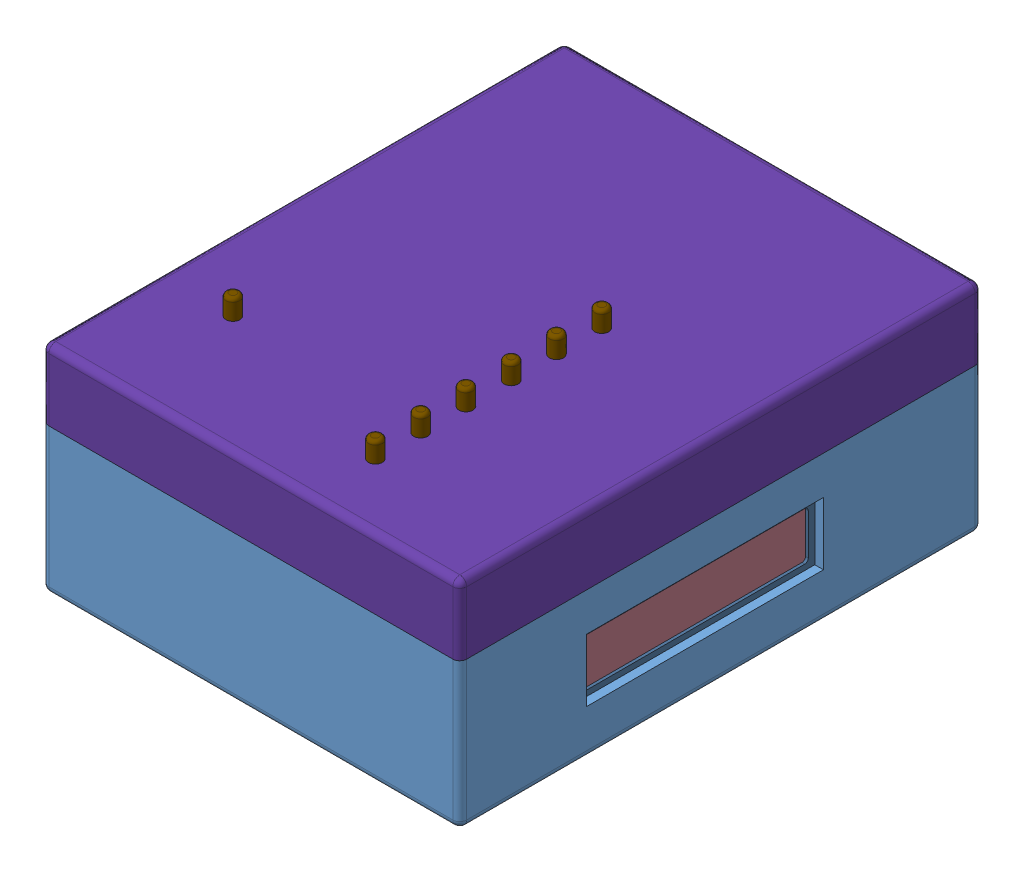
SolidWorks assembly final_enclosure, configuration Default. Lengths in mm.
Overall size (120.23 70.74 150.23).
39 component instances, 22 part files, 23 mates.
Components (placement in the parent):
- Assem60-1: Assem60 [Default] at (139.2059 48.6317 91.3679) size (120.23 50 150.23)
  - base1-1: base1 [Default] at (-81.3552 -3.1986 38.3093) size (120.23 45 150.23)
  - PCB2.step-1: PCB2.step [Default] at (-19.7622 13.9589 157.0703) x (0 0 -1) z (0 1 0) size (80.65 74.17 20.11)
  - Part39^Assem60-1: Part39^Assem60 [Default] at (-81.3552 1.8014 38.3093) x (1 0 0) z (0 1 0) (virtual)
  - BatteryHolder_9V_Eyelet_or_Pins-1: BatteryHolder_9V_Eyelet_or_Pins [Default] at (-87.1079 15.8014 -7.8784) x (-1 0 0) z (0 -1 0) size (62.36 30.2 20.5)
    - BatteryHolder_9V_Eyelet_or_Pins.step-1: BatteryHolder_9V_Eyelet_or_Pins.step [Default] at origin size (62.36 30.2 29.4)
      - Body_Housing.step-1: Body_Housing.step [Default] at origin size (54.5 30.2 20.5)
      - Body_Anode.step-1: Body_Anode.step [Default] at (22 -6.35 11.5) size (4.62 9.24 8)
      - Body_Cathode.step-1: Body_Cathode.step [Default] at (22 6.35 11.5) size (4.62 7.3 7.3)
      - Body_Pin.step-1: Body_Pin.step [Default] at origin size (0.8 0.8 19.4) (hidden)
      - Array_Pins.step-1: Array_Pins.step [Default] at origin size (0.8 13.5 19.4) (hidden)
      - Eyelet_bended_Cathode.step-1: Eyelet_bended_Cathode.step [Default] at (26.6 6.35 11.5) x (0 1 0) z (1 0 0) size (5.54 13.94 8.51)
      - Eyelet_bended_Anode.step-1: Eyelet_bended_Anode.step [Default] at (26.6 -6.35 11.5) x (0 1 0) z (1 0 0) size (5.54 13.94 8.51)
  - Part9^Assem60-1: Part9^Assem60 [Default] at (-21.3552 -3.1986 38.3093) x (0 0 -1) z (1 0 0) (virtual)
  - LCD.STEP-3: LCD.STEP [Default] at (-33.6552 19.8014 42.9691) x (0 0 -1) z (0 -1 0) size (80 18.3 36)
    - pcbboard.STEP-1: pcbboard.STEP [Default] at origin size (80 4.19 36)
    - 16pin_header__.STEP-1: 16pin_header__.STEP [Default] at (-32 0 -15.5) x (0 0 1) z (1 0 0) size (2.54 11.5 40.64)
    - lcd window.STEP-1: lcd window.STEP [Default] at (0 9 1.5) size (71.3 11.8 27.44)
    - backlight.STEP-1: backlight.STEP [Default] at (0 1.7 1.5) x (-1 0 0) z (0 0 -1) size (74.38 2.98 18)
    - conductor.STEP-1: conductor.STEP [Default] at (0 1.7 12.6) size (69.7 5.5 3)
    - conductor.STEP-2: conductor.STEP [Default] at (0 1.7 -9.6) size (69.7 5.5 3)
    - liquid crystal grabcad.STEP-1: liquid crystal grabcad.STEP [Default] at (0 7.9 1.5) size (68.5 2.2 25)
    - smt_resistor222.STEP-1: smt_resistor222.STEP [Default] at (-32.75 0 -5.25) x (0 0 1) z (1 0 0) size (1.8 0.6 4)
    - smt_resistor222.STEP-2: smt_resistor222.STEP [Default] at (-32.75 0 -2.75) x (0 0 1) z (1 0 0) size (1.8 0.6 4)
    - smt_resistor222.STEP-3: smt_resistor222.STEP [Default] at (-32.75 0 -0.25) x (0 0 1) z (1 0 0) size (1.8 0.6 4)
    - smt_resistor222.STEP-4: smt_resistor222.STEP [Default] at (-32.75 0 2.25) x (0 0 1) z (1 0 0) size (1.8 0.6 4)
    - smt_resistor222.STEP-5: smt_resistor222.STEP [Default] at (-32.75 0 4.75) x (0 0 1) z (1 0 0) size (1.8 0.6 4)
    - smt_resistor222.STEP-6: smt_resistor222.STEP [Default] at (-32.75 0 7.25) x (0 0 1) z (1 0 0) size (1.8 0.6 4)
    - smt_resistor101.STEP-1: smt_resistor101.STEP [Default] at (30.25 0 6.1) x (0 0 -1) z (-1 0 0) size (1.8 0.6 5.2)
    - smt_resistor101.STEP-2: smt_resistor101.STEP [Default] at (30.25 0 2.85) x (0 0 -1) z (-1 0 0) size (1.8 0.6 5.2)
  - support to LCD-1: support to LCD [Default] at (-35.6552 22.8014 43.6281) x (0 0 1) z (0 -1 0) size (84 4 42)
- top1-1: top1 [Default] at (57.8506 107.4331 129.6771) x (-1 0 0) z (0 0 1) size (120 44.59 150)
- button_head-5: button_head [Default] at (74.8266 67.6706 185.8851) x (0.999848 0 0.017421) z (-0.017421 0 0.999848) size (6 45.5 6)
- button_head-6: button_head [Default] at (74.8266 67.6706 172.8851) x (0.990283 0 -0.139069) z (0.139069 0 0.990283) size (6 45.5 6)
- button_head-8: button_head [Default] at (74.8266 67.6706 159.8851) x (-0.348775 0 0.937206) z (-0.937206 0 -0.348775) size (6 45.5 6)
- button_head-9: button_head [Default] at (74.8266 67.6706 146.8851) x (0.981061 0 -0.193697) z (0.193697 0 0.981061) size (6 45.5 6)
- button_head-10: button_head [Default] at (74.8266 67.6706 133.8851) x (0.977336 0 0.211696) z (-0.211696 0 0.977336) size (6 45.5 6)
- button_head-11: button_head [Default] at (74.8266 67.6706 120.8851) x (0.999981 0 0.006163) z (-0.006163 0 0.999981) size (6 45.5 6)
- button_head-13: button_head [Default] at (18.8596 67.6706 170.8411) x (-0.485367 0 0.87431) z (-0.87431 0 -0.485367) size (6 45.5 6)
Mates (geometry in assembly coordinates):
- Coincident1: coincident: plane of Assem60-1/base1-1 through (117.8506 87.4331 54.6771) normal (1 0 0); plane of top1-1 through (117.8506 87.4331 54.6771) normal (1 0 0)
- Coincident2: coincident: plane of Assem60-1/base1-1 through (-2.1494 87.4331 204.6771) normal (0 0 1); plane of top1-1 through (117.8506 87.4331 204.6771) normal (0 0 1)
- Coincident3: coincident: plane of Assem60-1/base1-1 through (57.8506 87.4331 129.6771) normal (0 1 0); plane of top1-1 through (57.8506 87.4331 129.6771) normal (0 -1 0)
- Concentric1: concentric: cylinder of top1-1 through (74.8266 107.4331 185.8851) axis (0 -1 0) radius 2; cylinder of button_head-5 through (74.8266 113.1706 185.8851) axis (0 -1 0) radius 2
- Concentric2: concentric: cylinder of top1-1 through (74.8266 107.4331 172.8851) axis (0 -1 0) radius 2; cylinder of button_head-6 through (74.8266 113.1706 172.8851) axis (0 -1 0) radius 2
- Concentric3: concentric: cylinder of top1-1 through (74.8266 107.4331 159.8851) axis (0 -1 0) radius 2; cylinder of button_head-8 through (74.8266 113.1706 159.8851) axis (0 -1 0) radius 2
- Concentric4: concentric: cylinder of top1-1 through (74.8266 107.4331 146.8851) axis (0 -1 0) radius 2; cylinder of button_head-9 through (74.8266 113.1706 146.8851) axis (0 -1 0) radius 2
- Concentric5: concentric: cylinder of top1-1 through (74.8266 107.4331 133.8851) axis (0 -1 0) radius 2; cylinder of button_head-10 through (74.8266 113.1706 133.8851) axis (0 -1 0) radius 2
- Concentric6: concentric: cylinder of top1-1 through (74.8266 107.4331 120.8851) axis (0 -1 0) radius 2; cylinder of button_head-11 through (74.8266 113.1706 120.8851) axis (0 -1 0) radius 2
- Coincident5: coincident: plane of Assem60-1/PCB2.step-1 through (74.4436 67.6706 186.1682) normal (0 1 0); plane of button_head-5 through (74.8266 67.6706 185.8851) normal (0 -1 0)
- Coincident6: coincident: plane of Assem60-1/PCB2.step-1 through (74.4436 67.6706 173.1682) normal (0 1 0); plane of button_head-6 through (74.8266 67.6706 172.8851) normal (0 -1 0)
- Coincident7: coincident: plane of Assem60-1/PCB2.step-1 through (74.4436 67.6706 160.1682) normal (0 1 0); plane of button_head-9 through (74.8266 67.6706 146.8851) normal (0 -1 0)
- Coincident8: coincident: plane of Assem60-1/PCB2.step-1 through (74.4436 67.6706 134.1682) normal (0 1 0); plane of button_head-10 through (74.8266 67.6706 133.8851) normal (0 -1 0)
- Coincident9: coincident: plane of Assem60-1/PCB2.step-1 through (74.4436 67.6706 121.1682) normal (0 1 0); plane of button_head-11 through (74.8266 67.6706 120.8851) normal (0 -1 0)
- Lock2: lock: unknown of top1-1; unknown of button_head-5
- Lock3: lock: unknown of top1-1; unknown of button_head-6
- Lock4: lock: unknown of top1-1; unknown of button_head-8
- Lock5: lock: unknown of top1-1; unknown of button_head-9
- Lock6: lock: unknown of top1-1; unknown of button_head-10
- Lock7: lock: unknown of top1-1; unknown of button_head-11
- Concentric7: concentric: cylinder of top1-1 through (18.8596 107.4331 170.8411) axis (0 -1 0) radius 2; cylinder of button_head-13 through (18.8596 113.1706 170.8411) axis (0 -1 0) radius 2
- Coincident10: coincident: plane of Assem60-1/PCB2.step-1 through (18.8596 67.6706 170.8412) normal (0 1 0); plane of button_head-13 through (18.8596 67.6706 170.8411) normal (0 -1 0)
- Lock8: lock: unknown of top1-1; unknown of button_head-13
